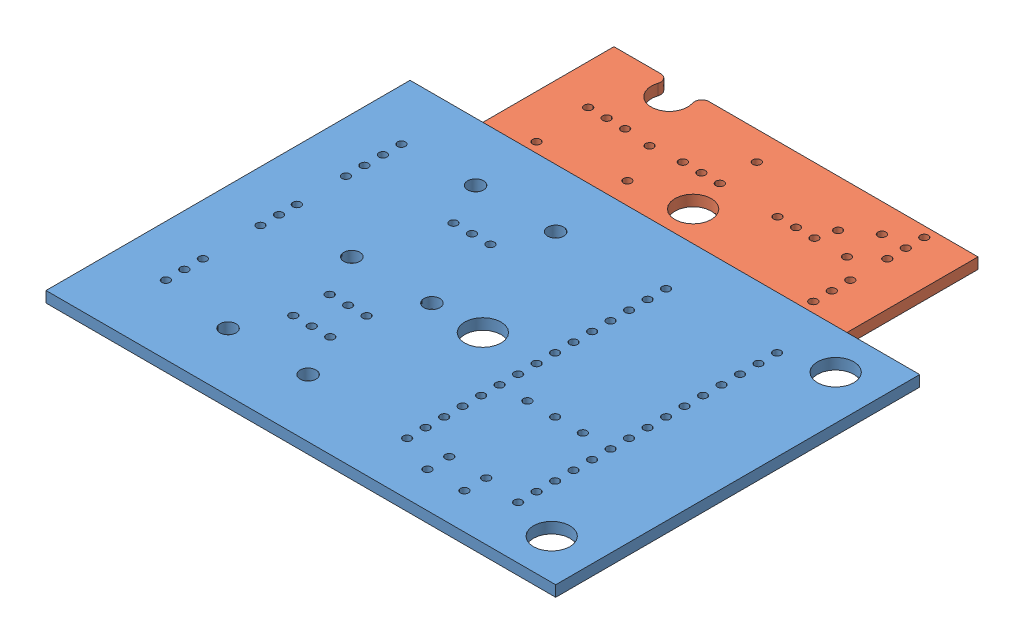
SolidWorks assembly Circuits, configuration Default. Lengths in mm.
Overall size (70 1.5 68).
3 component instances, 3 part files, 12 mates.
Components (placement in the parent):
- SampleShield V2-1: SampleShield V2 [Default] at origin size (70 1.5 50)
- SampleCircuitBoard-2: SampleCircuitBoard [Default] at (-10 1.5 -36.5) x (0 0 -1) z (-1 0 0) (suppressed, hidden)
- SampleFlashlightPCB-2: SampleFlashlightPCB [Default] at (0 0 -34) size (50 1.5 18)
Mates (geometry in assembly coordinates):
- Coincident1: coordinate: point of SampleShield V2-1
- Coincident2: coincident: plane of SampleShield V2-1 through (0 1.5 0) normal (0 1 0); plane of SampleCircuitBoard-1 through (24 1.5 36.5) normal (0 1 0)
- Coincident3: coincident aligned: plane of SampleShield V2-1 through (0 1.5 0) normal (0 1 0); plane of SampleFlashlightPCB-1 through (-10 1.5 32.5) normal (0 1 0)
- Coincident5: coincident anti-aligned: plane of SampleShield V2-1 through (-35 1.5 25) normal (0 0 1); plane of SampleFlashlightPCB-1 through (-35 1.5 25) normal (0 0 -1)
- Coincident7: coincident aligned: plane of SampleShield V2-1 through (-35 1.5 25) normal (-1 0 0); plane of SampleFlashlightPCB-1 through (-35 1.5 40) normal (-1 0 0)
- Coincident9: coincident: plane of SampleShield V2-1 through (-35 1.5 25) normal (0 0 1); plane of SampleCircuitBoard-1 through (33 1.5 25) normal (0 0 -1)
- Coincident10: coincident anti-aligned: plane of SampleCircuitBoard-1 through (15 1.5 48) normal (-1 0 0); plane of SampleFlashlightPCB-1 through (15 1.5 40) normal (1 0 0)
- Coincident22: coincident anti-aligned: plane of SampleShield V2-1 through (-35 1.5 -25) normal (0 0 -1); plane of SampleCircuitBoard-2 through (-19 0 -25) normal (0 0 1)
- Coincident23: coincident aligned: plane of SampleShield V2-1 through (0 0 0) normal (0 -1 0); plane of SampleCircuitBoard-2 through (-10 0 -36.5) normal (0 -1 0)
- Coincident28: coincident: plane of SampleShield V2-1 through (-35 1.5 -25) normal (0 0 -1); plane of SampleFlashlightPCB-2 through (-25 1.5 -25) normal (0 0 1)
- Coincident29: coincident: plane of SampleShield V2-1 through (0 1.5 0) normal (0 1 0); plane of SampleFlashlightPCB-2 through (0 1.5 -34) normal (0 1 0)
- Distance2: distance = 10 mm aligned: plane of SampleFlashlightPCB-2 through (25 1.5 -25) normal (1 0 0); plane of SampleShield V2-1 through (35 1.5 25) normal (1 0 0)
